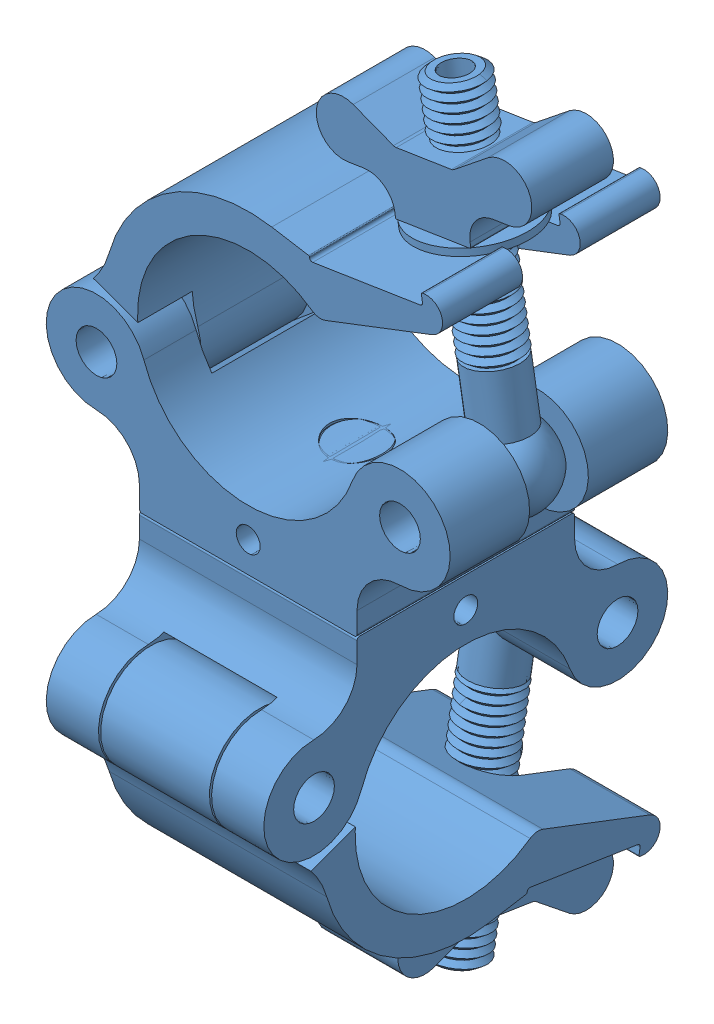
SolidWorks assembly GE-20006, configuration Drawing. Lengths in mm.
Overall size (97.52 204.17 97.52).
2 component instances, 1 part files, 3 mates.
Components (placement in the parent):
- GE-20007-1: GE-20007 [Default] at origin size (97.52 129.07 50.8)
- GE-20007-2: GE-20007 [Default] at (-23.5463 440.4613 -23.5463) x (0 0 -1) z (-1 0 0) size (97.52 129.07 50.8)
Mates (geometry in assembly coordinates):
- Coincident1: coincident anti-aligned: plane of GE-20007-1 through (-41.6013 220.2306 32.7451) normal (0 -1 0); plane of GE-20007-2 through (-56.2914 220.2306 18.0549) normal (0 1 0)
- Coincident2: coincident aligned: plane of GE-20007-1 through (-74.3463 224.4323 26.5507) normal (-1 0 0); plane of GE-20007-2 through (-74.3463 201.8852 25.4) normal (-1 0 0)
- Concentric1: concentric anti-aligned: circle of GE-20007-1; circle of GE-20007-2
